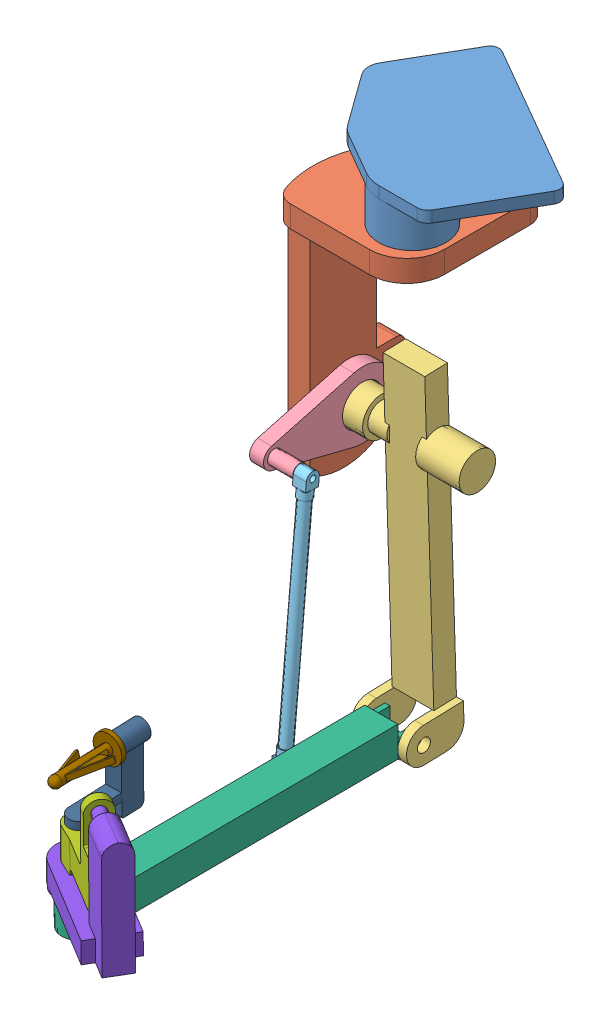
SolidWorks assembly MTM, configuration Default. Lengths in mm.
Overall size (277.7 571.58 649.44).
10 component instances, 10 part files, 23 mates.
Components (placement in the parent):
- Top Panel-1: Top Panel [Default] at (41.2771 0 -108.0726) x (0.866025 0 0.5) z (-0.5 0 0.866025) size (211 57 150.8)
- OutPitch_Shoulder-1: OutPitch_Shoulder [Default] at (87.2678 -44 -67.0959) size (158.75 288.37 165.1)
- ArmParellel-1: ArmParellel [Default] at (87.2678 -259.3696 -44.4959) x (1 0 0) z (0 -0.030855 0.999524) size (178 377.72 75)
- ArmParellel1-2: ArmParellel1 [Default] at (24.2678 -260.228 56.6004) x (1 0 0) z (0 -0.008492 0.999964) size (45 76.4 152)
- Link-1: Link [Default] at (60.7678 -399.358 69.2074) x (1 0 0) z (0 0.090243 0.99592) size (15 294.4 15)
- BottomArm-1: BottomArm [Default] at (87.2678 -532.6 -3.1572) x (1 0 0) z (0 0.999987 0.00503) size (44 393.6 39.5)
- WristPitch-1: WristPitch [Default] at (166.0445 -420.9491 392.5341) x (0.001963 -0.999964 -0.008274) z (0.855596 -0.002604 0.517638) size (115.77 40.55 105.5)
- WristPlatform-1: WristPlatform [Default] at (87.2678 -507.2092 344.5786) x (-0.855596 0.002604 -0.517638) z (0.517645 0.004303 -0.855585) size (164.45 137 56.91)
- WristRoll-1: WristRoll [Default] at (87.958 -391.4366 312.2033) x (0.323924 -0.94592 -0.01755) z (-0.945602 -0.324295 0.025884) size (32 73 46.11)
- WristYaw-1: WristYaw [Default] at (89.0919 -446.7138 345.7316) x (-0.999543 -0.002212 0.030158) z (-0.030175 0.008211 -0.999511) size (31.04 83 89.52)
Mates (geometry in assembly coordinates):
- Coincident26: coincident anti-aligned: plane of WristRoll-1 through (87.8071 -391.3956 307.2057) normal (-0.030175 0.008211 -0.999511); plane of WristYaw-1 through (87.8071 -391.3956 307.2057) normal (0.030175 -0.008211 0.999511)
- Concentric21: concentric aligned: circle of WristRoll-1; circle of WristYaw-1
- Coincident27: coincident anti-aligned: plane of WristPitch-1 through (100.9269 -446.8804 368.6697) normal (-0.001963 0.999964 0.008274); plane of WristYaw-1 through (104.629 -446.5545 330.1568) normal (0.001963 -0.999964 -0.008274)
- Concentric22: concentric aligned: circle of WristPitch-1; circle of WristYaw-1
- Coincident28: coincident anti-aligned: plane of WristPitch-1 through (148.8707 -389.3982 382.442) normal (0.855596 -0.002604 0.517638); plane of WristPlatform-1 through (148.8707 -389.3982 382.442) normal (-0.855596 0.002604 -0.517638)
- Concentric23: concentric anti-aligned: circle of WristPitch-1; circle of WristPlatform-1
- Concentric24: concentric anti-aligned: circle of WristPlatform-1; circle of BottomArm-1
- Coincident30: coincident anti-aligned: plane of OutPitch_Shoulder-1 through (88.7178 -44 -30.9959) normal (0 1 0); plane of Top Panel-1 through (87.2678 -44 -38.7959) normal (0 -1 0)
- Concentric25: concentric aligned: circle of OutPitch_Shoulder-1; circle of Top Panel-1
- Coincident35: coincident anti-aligned: plane of ArmParellel-1 through (65.2678 -537.1733 -46.0684) normal (1 0 0); plane of BottomArm-1 through (65.2678 -527.5849 -6.132) normal (-1 0 0)
- Concentric27: concentric aligned: circle of ArmParellel-1; circle of BottomArm-1
- Coincident36: coincident aligned: plane of BottomArm-1 through (68.2678 -551.853 345.3404) normal (-1 0 0); circle of Link-1
- Concentric28: concentric aligned: circle of BottomArm-1; circle of Link-1
- Concentric29: concentric: circle of Link-1; circle of ArmParellel1-2
- Concentric30: concentric anti-aligned: circle of ArmParellel-1; circle of ArmParellel1-2
- Concentric37: concentric aligned: circle of OutPitch_Shoulder-1; circle of ArmParellel1-2
- Distance1: distance = 150.6 mm: point of WristPlatform-1; plane of BottomArm-1 through (87.2678 -538.0605 -3.1846) normal (0 0.999987 0.00503)
- Coincident49: coincident aligned: plane of Top Panel-1; plane of assembly through (0 0 0) normal (0 1 0)
- Coincident51: coincident aligned: plane of OutPitch_Shoulder-1 through (87.2678 -44 -67.0959) normal (1 0 0); plane of ArmParellel-1
- Parallel6: parallel aligned: plane of ArmParellel-1; plane of assembly through (0 0 0) normal (1 0 0)
- Concentric40: concentric anti-aligned: cylinder of ArmParellel1-2 through (53.2678 -260.228 56.6004) axis (-1 0 0) radius 8; cylinder of Link-1 through (43.3683 -260.228 56.6004) axis (1 0 0) radius 3.5
- Coincident52: coincident aligned: plane of Top Panel-1 through (131.4375 13 0) normal (0 0 1); plane of assembly through (0 0 0) normal (0 0 1)
- Coincident53: coincident anti-aligned: plane of ArmParellel1-2 through (53.2678 -260.228 56.6004) normal (1 0 0); plane of Link-1 through (53.2678 -253.4355 48.4542) normal (-1 0 0)
